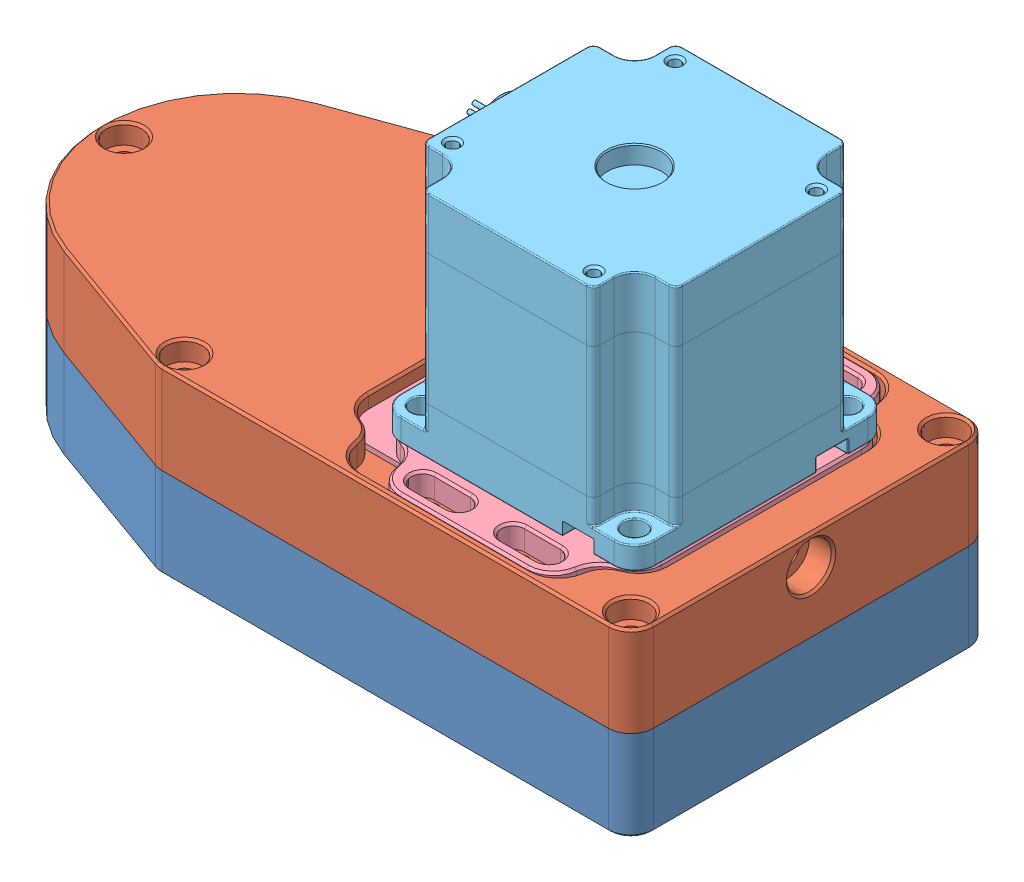
SolidWorks assembly Z Axis Motor Module, configuration Défaut. Lengths in mm.
Overall size (157.5 91 80).
9 component instances, 9 part files, 26 mates.
Components (placement in the parent):
- Z Axis Motor Module Bot-1: Z Axis Motor Module Bot [Défaut] at (52.5 0 0) size (157.5 20 80)
- Z Axis Motor Module Top-1: Z Axis Motor Module Top [Défaut] at (52.5 20 0) x (1 0 0) z (0 1 0) size (157.5 80 20)
- Z Axis Pulley 17XL037-1: Z Axis Pulley 17XL037 [Default] at (0 26 0) x (0 -1 0) z (-0.435877 0 0.900006) size (16 32 32)
- Tendeur Moteur-1: Tendeur Moteur [Défaut] at (88.3 30 0) x (0 0 -1) z (0 1 0) size (76 68.2 10)
- NEMA23 Stepper Motor-1: NEMA23 Stepper Motor [57BYGH201] at (88.3 40 0) x (0 0 1) z (0 -1 0) size (56.69 64.04 72)
- Motor Pulley 17XL037 6.35mm Bore-1: Motor Pulley 17XL037 6.35mm Bore [Default] at (88.3 14 0) x (0 1 0) z (0.510058 0 -0.86014) size (19 32 32)
- Bearing 6001-1: Bearing 6001 [Défaut] at (0 3 0) x (0 1 0) z (0.954368 0 -0.298632) size (8 28 28)
- Wedge 3x3x14-1: Wedge 3x3x14 [Défaut] at (3.15 20 1.5256) x (0 1 0) z (0.900006 0 0.435877) size (14 3 3)
- Motor Module Washer-1: Motor Module Washer [Défaut] at (0 27 0) x (1 0 0) z (0 1 0) size (21 21 2)
Mates (geometry in assembly coordinates):
- Distance1: distance = 52.5 mm aligned: plane of Z Axis Motor Module Bot-1 through (52.5 0 0) normal (1 0 0); plane of assembly through (0 0 0) normal (1 0 0)
- Coïncidente2: coincident aligned: plane of Z Axis Motor Module Bot-1 through (52.5 0 0) normal (0 0 1); plane of assembly through (0 0 0) normal (0 0 1)
- Coïncidente3: coincident aligned: plane of Z Axis Motor Module Bot-1 through (52.5 0 0) normal (0 1 0); plane of assembly through (0 0 0) normal (0 1 0)
- Coaxiale1: concentric aligned: cylinder of Z Axis Motor Module Bot-1 through (0 20 0) axis (0 -1 0) radius 30; cylinder of Z Axis Motor Module Top-1 through (0 40 0) axis (0 -1 0) radius 30
- Coïncidente4: coincident anti-aligned: plane of Z Axis Motor Module Bot-1 through (52.5 20 0) normal (0 1 0); plane of Z Axis Motor Module Top-1 through (0 20 0) normal (0 -1 0)
- Coïncidente5: coincident aligned: plane of Z Axis Motor Module Bot-1 through (127.5 20 0) normal (1 0 0); plane of Z Axis Motor Module Top-1 through (127.5 40 -40) normal (1 0 0)
- Coïncidente6: coincident anti-aligned: plane of Z Axis Motor Module Top-1 through (52.5 35 0) normal (0 1 0); plane of Tendeur Moteur-1 through (88.3 35 0) normal (0 -1 0)
- Largeur1: width anti-aligned: plane of Z Axis Motor Module Top-1 through (52.5 35 -38.1) normal (0 0 1); plane of Z Axis Motor Module Top-1 through (52.5 35 38.1) normal (0 0 -1); plane of Tendeur Moteur-1 through (108.3 40 -38) normal (0 0 -1); plane of Tendeur Moteur-1 through (108.3 40 38) normal (0 0 1)
- Coïncidente7: coincident anti-aligned: plane of Tendeur Moteur-1 through (88.3 40 0) normal (0 1 0); plane of ? through (56.6786 40 -28.2) normal (0 -1 0)
- Coaxiale2: concentric anti-aligned: cylinder of Tendeur Moteur-1 through (64.73 40 23.57) axis (0 1 0) radius 2.1; cylinder of ? through (61.3086 96.001 23.57) axis (0 -1 0) radius 2.5
- Coaxiale3: concentric anti-aligned: cylinder of Tendeur Moteur-1 through (111.87 40 23.57) axis (0 1 0) radius 2.1; cylinder of ? through (108.4486 96.001 23.57) axis (0 -1 0) radius 2.5
- Coïncidente8: coincident anti-aligned: plane of Tendeur Moteur-1 through (88.3 40 0) normal (0 1 0); plane of NEMA23 Stepper Motor-1 through (88.3 40 0) normal (0 -1 0)
- Coaxiale4: concentric anti-aligned: cylinder of Tendeur Moteur-1 through (64.73 40 23.57) axis (0 1 0) radius 2.1; cylinder of NEMA23 Stepper Motor-1 through (64.73 40 23.57) axis (0 -1 0) radius 2.5
- Coaxiale5: concentric anti-aligned: cylinder of Tendeur Moteur-1 through (111.87 40 23.57) axis (0 1 0) radius 2.1; cylinder of NEMA23 Stepper Motor-1 through (111.87 40 23.57) axis (0 -1 0) radius 2.5
- Coaxiale6: concentric anti-aligned: cylinder of Z Axis Motor Module Bot-1 through (0 -39.598 0) axis (0 1 0) radius 14; cylinder of Bearing 6001-1 through (0 3 0) axis (0 -1 0) radius 14
- Coïncidente9: coincident anti-aligned: plane of Z Axis Motor Module Bot-1 through (52.5 3 0) normal (0 1 0); plane of Bearing 6001-1 through (3.6911 3 11.796) normal (0 -1 0)
- Coaxiale7: concentric aligned: cylinder of NEMA23 Stepper Motor-1 through (88.3 19 0) axis (0 1 0) radius 3.175; cylinder of Motor Pulley 17XL037 6.35mm Bore-1 through (88.3 13 0) axis (0 1 0) radius 3.175
- Coaxiale8: concentric aligned: cylinder of Z Axis Pulley 17XL037-1 through (0 27 0) axis (0 -1 0) radius 5; cylinder of Bearing 6001-1 through (0 3 0) axis (0 -1 0) radius 6
- Coïncidente10: coincident anti-aligned: plane of Z Axis Pulley 17XL037-1 through (0 11 0) normal (0 -1 0); plane of Bearing 6001-1 through (1.8814 11 6.0125) normal (0 1 0)
- Coïncidente11: coincident aligned: plane of Z Axis Pulley 17XL037-1 through (0 27 0) normal (0 1 0); plane of Motor Pulley 17XL037 6.35mm Bore-1 through (88.3 27 0) normal (0 1 0)
- Distance2: distance = 1 mm anti-aligned: plane of Tendeur Moteur-1 through (116.5 40 -28.2) normal (1 0 0); plane of Z Axis Motor Module Top-1 through (117.5 35 0) normal (-1 0 0)
- Coïncidente30: coincident anti-aligned: plane of Z Axis Pulley 17XL037-1 through (5.1962 27 4.1832) normal (-0.900006 0 -0.435877); plane of Wedge 3x3x14-1 through (5.85 14.5 2.8332) normal (0.900006 0 0.435877)
- Coïncidente31: coincident anti-aligned: plane of Z Axis Pulley 17XL037-1 through (5.1962 27 4.1832) normal (0.435877 0 -0.900006); plane of Wedge 3x3x14-1 through (5.1962 14.5 4.1832) normal (-0.435877 0 0.900006)
- Tangent1: tangent aligned: plane of Z Axis Pulley 17XL037-1 through (0 27 0) normal (0 1 0); cylinder of Wedge 3x3x14-1 through (5.85 25.5 2.8332) axis (-0.900006 0 -0.435877) radius 1.5
- Coïncidente32: coincident anti-aligned: plane of Z Axis Pulley 17XL037-1 through (0 27 0) normal (0 1 0); plane of Motor Module Washer-1 through (0 27 0) normal (0 -1 0)
- Coaxiale27: concentric aligned: cylinder of Z Axis Pulley 17XL037-1 through (0 27 0) axis (0 -1 0) radius 5; cylinder of Motor Module Washer-1 through (0 29 0) axis (0 -1 0) radius 10.5
